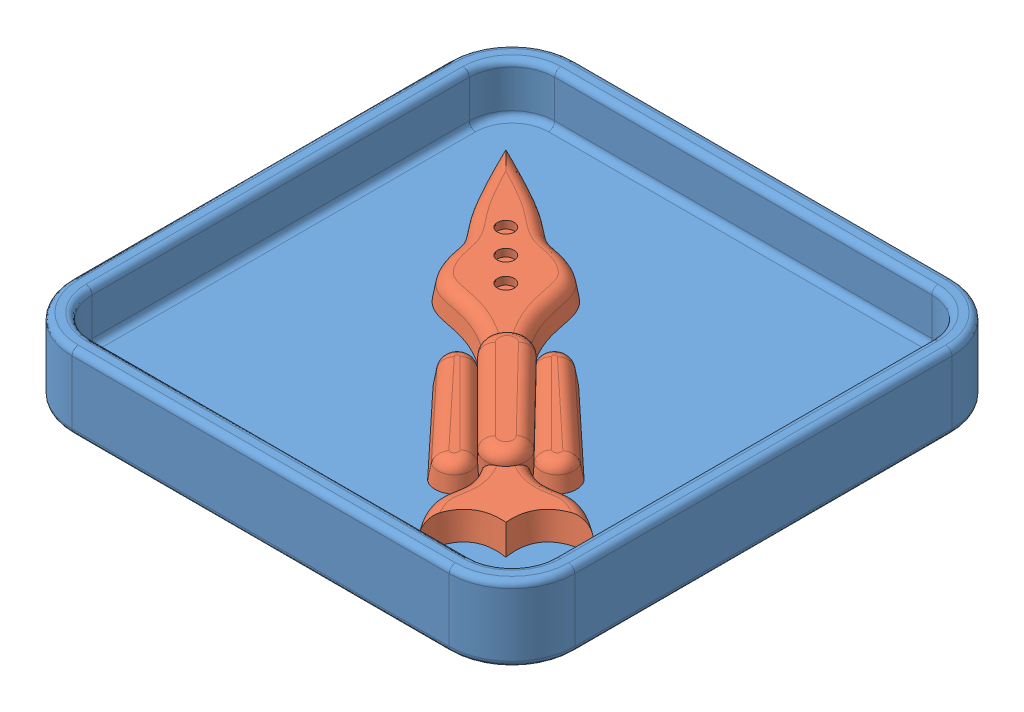
SolidWorks assembly BlueSpaceShip, configuration Default. Lengths in mm.
Overall size (40 6 40).
2 component instances, 2 part files, 2 mates.
Components (placement in the parent):
- Tile-1: Tile [Default] at (12.0316 18.0545 32.1109) size (40 6 40)
- BlueSpaceShip-1: BlueSpaceShip [Default] at (11.6316 20.0545 32.2012) size (32.02 3.06 32.19)
Mates (geometry in assembly coordinates):
- Coincident1: coincident anti-aligned: plane of Tile-1 through (-2.9684 20.0545 47.1109) normal (0 1 0); plane of BlueSpaceShip-1 through (10.901 20.0545 26.7757) normal (0 -1 0)
- Coincident2: coincident aligned: line of Tile-1 through (-5.8684 20.0545 17.1109) axis (0 0 1); line of BlueSpaceShip-1 through (-5.8684 20.0545 14.7012) axis (0 0 1)
